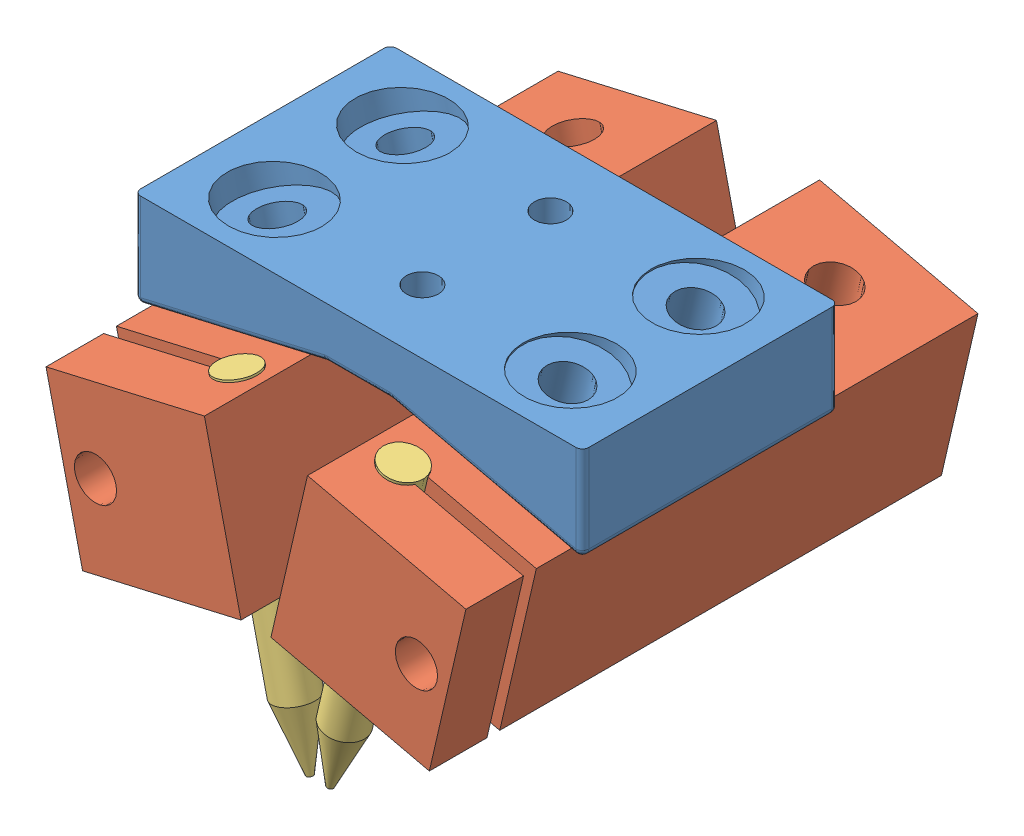
SolidWorks assembly welder_assy, configuration Default. Lengths in mm.
Overall size (70 60.12 80).
5 component instances, 3 part files, 8 mates.
Components (placement in the parent):
- Block_Holder-1: Block_Holder [Default] at origin size (70 14.74 40)
- Bus_Block-1: Bus_Block [Default] at (7.9131 -24.2412 16) x (0.97437 0.224951 0) z (0 0 1) size (25.4 25.4 80)
- Bus_Block-2: Bus_Block [Default] at (67.8007 0.5078 16) x (-0.97437 0.224951 0) z (0 0 1) size (25.4 25.4 80)
- Carbide_Electrode-1: Carbide_Electrode [Default] at (22.0063 5.4005 6) x (-0.018408 -0.00425 0.999822) z (0.974196 0.224911 0.018892) size (7.46 50.8 7.07)
- Carbide_Electrode-2: Carbide_Electrode [Default] at (48.0112 5.4765 6) x (-0.450818 0.10408 0.886527) z (0.863806 -0.199425 0.462677) size (7.46 50.8 7.07)
Mates (geometry in assembly coordinates):
- Coincident1: coincident anti-aligned: plane of Block_Holder-1 through (30 6.926 -40) normal (0.224951 -0.97437 0); plane of Bus_Block-1 through (2.1993 0.5078 16) normal (-0.224951 0.97437 0)
- Coincident2: coincident anti-aligned: plane of Block_Holder-1 through (70 0 -40) normal (-0.224951 -0.97437 0); plane of Bus_Block-2 through (67.8007 0.5078 16) normal (0.224951 0.97437 0)
- Coincident3: coincident aligned: plane of Bus_Block-1 through (2.1993 0.5078 16) normal (0 0 1); plane of Bus_Block-2 through (62.0869 -24.2412 16) normal (0 0 1)
- Concentric1: concentric aligned: cylinder of Bus_Block-1 through (22.0765 5.0968 6) axis (-0.224951 0.97437 0) radius 3.175; cylinder of Carbide_Electrode-1 through (31.1843 -34.3538 6) axis (-0.224951 0.97437 0) radius 3.175
- Distance4: distance = 5 mm aligned: plane of Bus_Block-1 through (7.9131 -24.2412 5) normal (0 0 1); plane of Block_Holder-1 through (0 0 0) normal (0 0 1)
- Coincident9: coincident anti-aligned: circle of Bus_Block-2; cylinder of Carbide_Electrode-2 through (38.8332 -34.2778 6) axis (0.224951 0.97437 0) radius 3.175
- Distance5: distance = 1 mm: plane of Bus_Block-1 through (2.1993 0.5078 16) normal (-0.97437 -0.224951 0); line of Block_Holder-1 through (1.225 0.2828 -1) axis (0 0 -1)
- Distance6: distance = 1 mm: plane of Bus_Block-2 through (62.0869 -24.2412 16) normal (0.97437 -0.224951 0); line of Block_Holder-1 through (68.775 0.2828 -39) axis (0 0 1)
